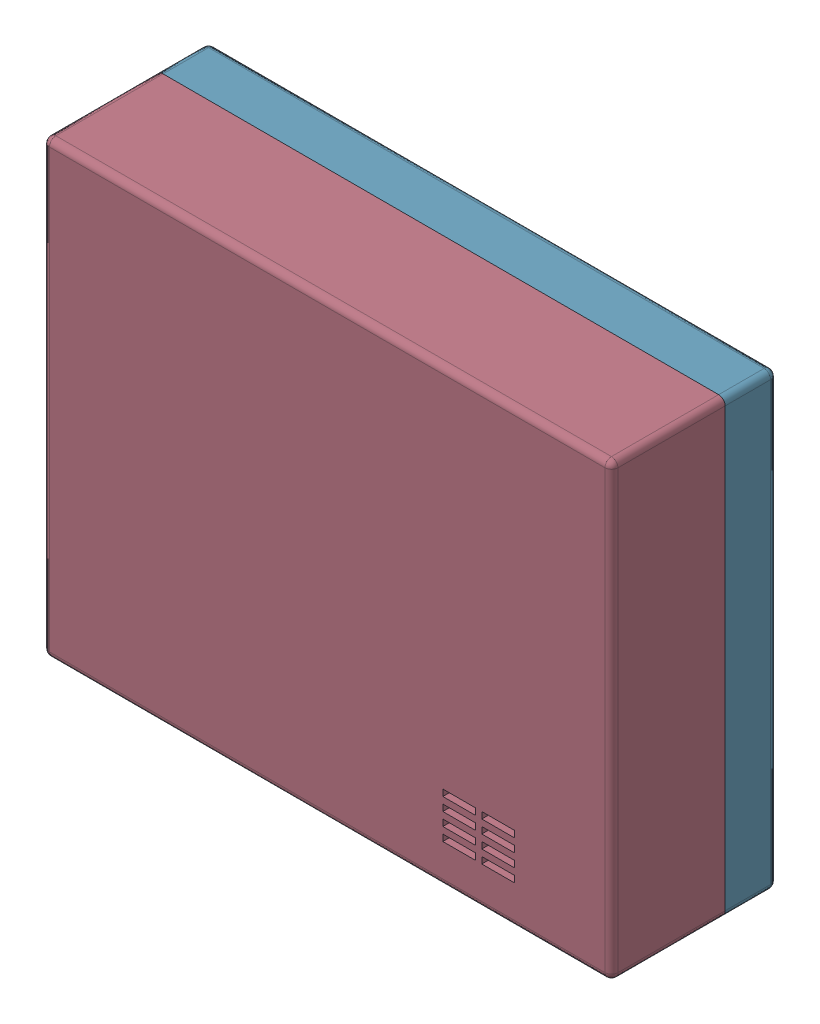
SolidWorks assembly AlarmClock, configuration Default. Lengths in mm.
Overall size (175.05 138.6 51).
68 component instances, 20 part files, 11 mates.
Components (placement in the parent):
- alarmClock.step-1: alarmClock.step [Default] at origin size (170.05 133.6 28.9)
  - Board.step-1: Board.step [Default] at origin size (170.05 133.6 0.41)
    - Open CASCADE STEP translator 6.8 2.1.1.step-1: Open CASCADE STEP translator 6.8 2.1.1.step [Default] at (0 0 -0.4115) size (170.05 133.6 0.41)
  - S2.step-1: S2.step [Default] at origin size (7.7 6.02 7.5)
    - Push_Tactile_Button_SPST-NO_6x6mm_L=5mm_Omron_B3F-1020.step-1: Push_Tactile_Button_SPST-NO_6x6mm_L=5mm_Omron_B3F-1020.step [Default] at (129.4886 88.4833 -0.4115) x (1 0 0) z (0 0 -1) size (7.7 6.02 7.5)
  - XTAL1.step-1: XTAL1.step [Default] at origin size (11.2 4.85 7)
    - HC-49S.step-1: HC-49S.step [Default] at (53.8233 118.9852 0) x (-1 0 0) z (0 0 1) size (11.2 4.85 7)
  - U2.step-1: U2.step [Default] at origin size (35.6 10.2 7.98)
    - Atmega328_RGB8421504.step-1: Atmega328_RGB8421504.step [Default] at (121.1581 43.6244 0) x (1 0 0) z (0 0 1) size (35.6 10.2 7.98)
      - Microcontroller_Hub1.step-1: Microcontroller_Hub1.step [Default] at origin size (35.6 10.2 5.4)
      - Microcontroller1.step-1: Microcontroller1.step [Default] at (0 0 4.6331) size (35.6 7.9 3.98)
  - U1.step-1: U1.step [Default] at origin size (4.5 10.2 28.9)
    - l7805cv.step-1: l7805cv.step [Default] at (48.8793 45.7113 0) x (0 1 0) z (1 0 0) size (10.2 28.9 4.5)
  - S4.step-1: S4.step [Default] at origin size (7.7 6.02 7.5)
    - Push_Tactile_Button_SPST-NO_6x6mm_L=5mm_Omron_B3F-1020.step-1: Push_Tactile_Button_SPST-NO_6x6mm_L=5mm_Omron_B3F-1020.step [Default] at (94.4366 88.6743 -0.4115) x (1 0 0) z (0 0 -1) size (7.7 6.02 7.5)
  - S3.step-1: S3.step [Default] at origin size (7.7 6.02 7.5)
    - Push_Tactile_Button_SPST-NO_6x6mm_L=5mm_Omron_B3F-1020.step-1: Push_Tactile_Button_SPST-NO_6x6mm_L=5mm_Omron_B3F-1020.step [Default] at (111.7086 88.6743 -0.4115) x (1 0 0) z (0 0 -1) size (7.7 6.02 7.5)
  - S1.step-1: S1.step [Default] at origin size (7.7 6.02 7.5)
    - Push_Tactile_Button_SPST-NO_6x6mm_L=5mm_Omron_B3F-1020.step-1: Push_Tactile_Button_SPST-NO_6x6mm_L=5mm_Omron_B3F-1020.step [Default] at (146.2526 88.6743 -0.4115) x (1 0 0) z (0 0 -1) size (7.7 6.02 7.5)
  - R8.step-1: R8.step [Default] at origin size (3.6 13.25 6.2)
    - RES-0.5W-H-MF.step-1: RES-0.5W-H-MF.step [Default] at (61.3429 45.3092 0) x (0 1 0) z (0 0 1) size (13.25 3.6 6.2)
  - R7.step-1: R7.step [Default] at origin size (3.6 13.25 6.2)
    - RES-0.5W-H-MF.step-1: RES-0.5W-H-MF.step [Default] at (71.376 63.2162 0) x (0 1 0) z (0 0 1) size (13.25 3.6 6.2)
  - R6.step-1: R6.step [Default] at origin size (3.6 13.25 6.2)
    - RES-0.5W-H-MF.step-1: RES-0.5W-H-MF.step [Default] at (167.638 62.5138 0) x (0 -1 0) z (0 0 1) size (13.25 3.6 6.2)
  - R5.step-1: R5.step [Default] at origin size (3.6 13.25 6.2)
    - RES-0.5W-H-MF.step-1: RES-0.5W-H-MF.step [Default] at (81.028 63.4702 0) x (0 1 0) z (0 0 1) size (13.25 3.6 6.2)
  - R4.step-1: R4.step [Default] at origin size (13.25 3.6 6.2)
    - RES-0.5W-H-MF.step-1: RES-0.5W-H-MF.step [Default] at (118.3342 66.673 0) x (1 0 0) z (0 0 1) size (13.25 3.6 6.2)
  - R3.step-1: R3.step [Default] at origin size (3.6 13.25 6.2)
    - RES-0.5W-H-MF.step-1: RES-0.5W-H-MF.step [Default] at (91.3149 63.2162 0) x (0 1 0) z (0 0 1) size (13.25 3.6 6.2)
  - R2.step-1: R2.step [Default] at origin size (3.6 13.25 6.2)
    - RES-0.5W-H-MF.step-1: RES-0.5W-H-MF.step [Default] at (157.1656 62.4995 0) x (0 -1 0) z (0 0 1) size (13.25 3.6 6.2)
  - R1.step-1: R1.step [Default] at origin size (3.6 13.25 6.2)
    - RES-0.5W-H-MF.step-1: RES-0.5W-H-MF.step [Default] at (146.687 62.5812 0) x (0 1 0) z (0 0 1) size (13.25 3.6 6.2)
  - POT1.step-1: POT1.step [Default] at origin size (4.96 9.53 14.05)
    - 3296Y.step-1: 3296Y.step [Default] at (49.8511 89.4058 0) x (0 1 0) z (0 0 1) size (9.53 4.96 14.05)
      - body.step-1: body.step [Default] at (0 -3.68 0) size (9.53 4.96 10.03)
      - adj.step-1: adj.step [Default] at (-3.495 0.01 10.03) size (2.19 2.19 1.52)
      - Open CASCADE STEP translator 6.8 2.17.1.3.step-1: Open CASCADE STEP translator 6.8 2.17.1.3.step [Default] at origin size (5.59 3.05 3.38)
  - DS1.step-1: DS1.step [Default] at origin size (80 36 13.5)
    - RC1602B-BIW-CSV--3DModel-STEP-56544.step-1: RC1602B-BIW-CSV--3DModel-STEP-56544.step [Default] at (120.7809 121.924 -0.4115) x (-1 0 0) z (0 -1 0) size (80 13.5 36)
  - C4.step-1: C4.step [Default] at origin size (5.5 5.5 15.01)
    - CAP_RAD_D5x11_POL_BK.step-1: CAP_RAD_D5x11_POL_BK.step [Default] at (180.3401 101.4521 0) x (-1 0 0) z (0 0 1) size (5.5 5.5 15.01)
  - C3.step-1: C3.step [Default] at origin size (5.5 5.5 15.01)
    - CAP_RAD_D5x11_POL_BK.step-1: CAP_RAD_D5x11_POL_BK.step [Default] at (53.8689 106.0288 0) x (0 -1 0) z (0 0 1) size (5.5 5.5 15.01)
  - C2.step-1: C2.step [Default] at origin size (5.5 5.5 15.01)
    - CAP_RAD_D5x11_POL_BK.step-1: CAP_RAD_D5x11_POL_BK.step [Default] at (180.4879 119.2368 0) x (0 -1 0) z (0 0 1) size (5.5 5.5 15.01)
  - C1.step-1: C1.step [Default] at origin size (5.5 5.5 15.01)
    - CAP_RAD_D5x11_POL_BK.step-1: CAP_RAD_D5x11_POL_BK.step [Default] at (53.8271 131.0639 0) x (0 1 0) z (0 0 1) size (5.5 5.5 15.01)
- Part1^AlarmClock-1: Part1^AlarmClock [Default] at origin size (175.05 138.6 35) (virtual)
- Part2^AlarmClock-1: Part2^AlarmClock [Default] x (-1 0 0) z (0 0 -1) size (175.05 138.6 16) (virtual)
- BatteryHolder_Keystone_1012_2xAA (1).step-3: BatteryHolder_Keystone_1012_2xAA (1).step [Default] at (121.0573 107.9 33) x (1 0 0) z (0 0 -1) size (68.98 33.99 20.29)
  - battery_AA_assembl.step-1: battery_AA_assembl.step [Default] at (25.201 -7.21 8.5) x (0 0.467529 0.883978) z (0 -0.883978 0.467529) size (14.48 50.7 14.48)
    - AA Battery_new.step-1: AA Battery_new.step [Default] at origin size (14.48 49.01 14.48)
    - bung_battery.step-1: bung_battery.step [Default] at (0 46.067 0) size (13.2 2 13.2)
    - grafite_electrode.step-1: grafite_electrode.step [Default] at (0 5.4 0) x (0.966043 0 -0.258381) z (0.258381 0 0.966043) size (3 45 3)
    - cap.step-1: cap.step [Default] at (0 48.2 0) size (4.01 2.5 4.01)
  - battery_AA_assembl-1.step-1: battery_AA_assembl-1.step [Default] at (-25.201 7.21 8.5) x (0 -0.467529 0.883978) z (0 0.883978 0.467529) size (14.48 50.7 14.48)
    - AA Battery_new.step-1: AA Battery_new.step [Default] at origin size (14.48 49.01 14.48)
    - bung_battery.step-1: bung_battery.step [Default] at (0 46.067 0) size (13.2 2 13.2)
    - grafite_electrode.step-1: grafite_electrode.step [Default] at (0 5.4 0) x (0.966043 0 -0.258381) z (0.258381 0 0.966043) size (3 45 3)
    - cap.step-1: cap.step [Default] at (0 48.2 0) size (4.01 2.5 4.01)
  - AAx2 SMT 422 Battery Holder.step-1: AAx2 SMT 422 Battery Holder.step [Default] x (1 0 0) z (0 -1 0) size (59.9 16.85 30)
  - connector.step-1: connector.step [Default] at (27.65 7.2 0) x (1 0 0) z (0 -1 0) size (9.41 15 6.35)
  - connector.step-2: connector.step [Default] at (-27.65 7.2 0) x (-1 0 0) z (0 1 0) size (9.41 15 6.35)
  - connector.step-3: connector.step [Default] at (27.65 -7.2 0) x (1 0 0) z (0 -1 0) size (9.41 15 6.35)
  - connector.step-4: connector.step [Default] at (-27.65 -7.2 0) x (-1 0 0) z (0 1 0) size (9.41 15 6.35)
Mates (geometry in assembly coordinates):
- InPlace1: in place: plane of alarmClock.step-1/Board.step-1/Open CASCADE STEP translator 6.8 2.1.1.step-1 through (34.671 18.796 0) normal (0 0 1); plane of Part1^AlarmClock-1 through (0 0 0) normal (0 0 1); moOrthogonalPlaneRef_w of alarmClock.step-1/Board.step-1/Open CASCADE STEP translator 6.8 2.1.1.step-1 through (34.671 18.796 0) normal (0 0 1); plane of Part1^AlarmClock-1 through (0 0 0) normal (0 1 0); plane of alarmClock.step-1/Board.step-1/Open CASCADE STEP translator 6.8 2.1.1.step-1 through (34.671 18.796 0) normal (0 0 1); plane of Part1^AlarmClock-1 through (0 0 0) normal (1 0 0); plane of alarmClock.step-1/Board.step-1/Open CASCADE STEP translator 6.8 2.1.1.step-1 through (34.671 18.796 0) normal (0 0 1); unknown of Part1^AlarmClock-1
- Coincident1: coincident aligned: plane of alarmClock.step-1/Board.step-1/Open CASCADE STEP translator 6.8 2.1.1.step-1; plane of Part1^AlarmClock-1
- Coincident2: coincident aligned: moOrthogonalPlaneRef_w of alarmClock.step-1/Board.step-1/Open CASCADE STEP translator 6.8 2.1.1.step-1 through (0 0 0) normal (0 1 0); plane of Part1^AlarmClock-1 through (0 0 0) normal (0 1 0)
- Coincident3: coincident anti-aligned: moOrthogonalPlaneRef_w of alarmClock.step-1/Board.step-1/Open CASCADE STEP translator 6.8 2.1.1.step-1 through (0 0 0) normal (-1 0 0); plane of Part1^AlarmClock-1 through (0 0 0) normal (1 0 0)
- InPlace2: in place: plane of Part1^AlarmClock-1 through (0 0 0) normal (0 0 -1); plane of Part2^AlarmClock-1 through (0 0 0) normal (0 0 -1); plane of Part1^AlarmClock-1 through (0 0 0) normal (0 0 -1); plane of Part2^AlarmClock-1 through (0 0 0) normal (0 1 0); plane of Part1^AlarmClock-1 through (0 0 0) normal (0 0 -1); plane of Part2^AlarmClock-1 through (0 0 0) normal (-1 0 0); plane of Part1^AlarmClock-1 through (0 0 0) normal (0 0 -1); unknown of Part2^AlarmClock-1
- Coincident4: coincident aligned: plane of Part1^AlarmClock-1; plane of Part2^AlarmClock-1
- Coincident5: coincident aligned: moOrthogonalPlaneRef_w of Part1^AlarmClock-1 through (0 0 0) normal (0 1 0); plane of Part2^AlarmClock-1 through (0 0 0) normal (0 1 0)
- Coincident6: coincident anti-aligned: moOrthogonalPlaneRef_w of Part1^AlarmClock-1 through (0 0 0) normal (1 0 0); plane of Part2^AlarmClock-1 through (0 0 0) normal (-1 0 0)
- Distance5: distance = 0 mm anti-aligned: plane of BatteryHolder_Keystone_1012_2xAA (1).step-3/AAx2 SMT 422 Battery Holder.step-1 through (121.0573 107.9 33) normal (0 0 1); plane of Part1^AlarmClock-1 through (0 0 33) normal (0 0 -1)
- Distance3: distance = 30 mm anti-aligned: plane of BatteryHolder_Keystone_1012_2xAA (1).step-3/AAx2 SMT 422 Battery Holder.step-1 through (91.1073 122.9 18.15) normal (0 1 0); plane of Part1^AlarmClock-1 through (32.171 152.9 35) normal (0 -1 0)
- Distance6: distance = 56.9363 mm anti-aligned: plane of BatteryHolder_Keystone_1012_2xAA (1).step-3/AAx2 SMT 422 Battery Holder.step-1 through (91.1073 122.9 18.15) normal (-1 0 0); plane of Part1^AlarmClock-1 through (34.171 154.9 35) normal (1 0 0)
